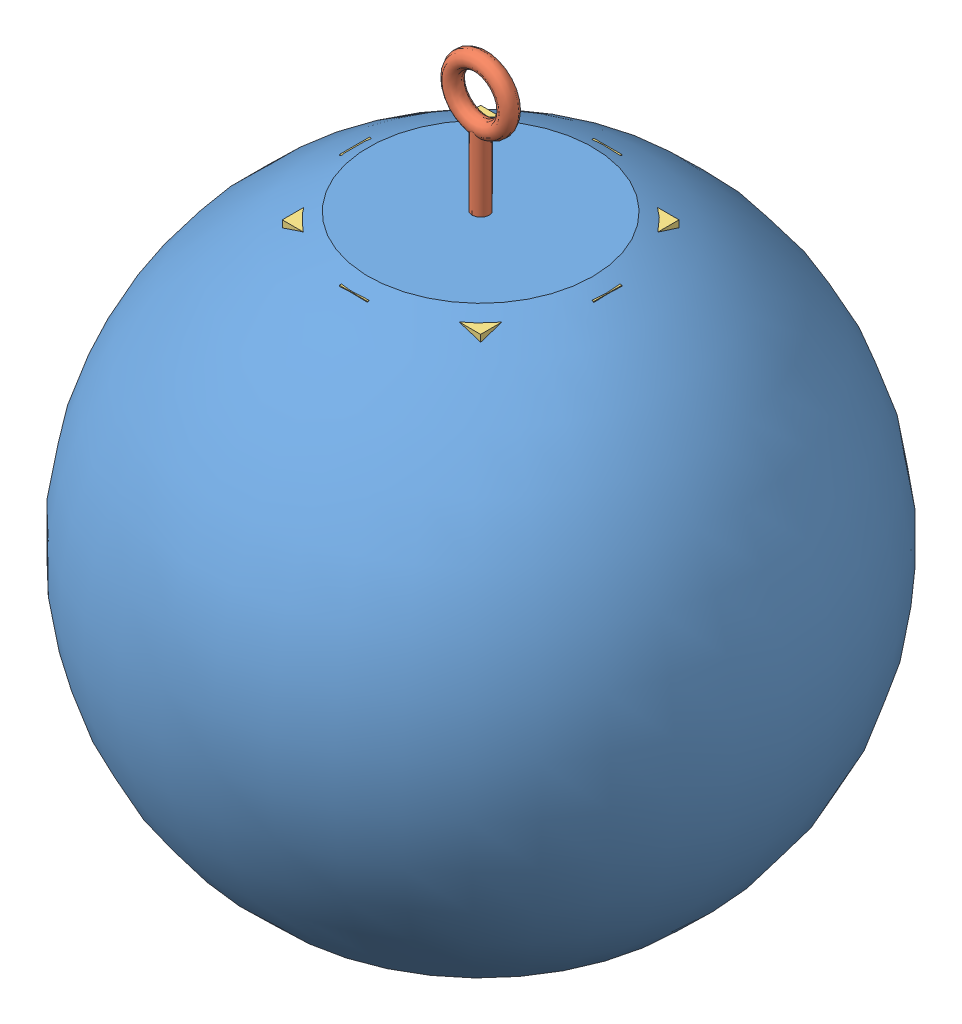
SolidWorks assembly final assembly, configuration Default. Lengths in mm.
Overall size (110 127.03 110).
4 component instances, 3 part files, 3 mates.
Components (placement in the parent):
- orb-1: orb [Default] at origin size (110 102.47 110)
- skeleton_assy-1: skeleton_assy [Default] at (-0.2 37.3 -0.2) size (75 120.8 75)
  - mount-1: mount [Default] at origin size (25 38.5 25)
  - Skeleton_9-1: Skeleton_9 [Default] at (0.2 -37.3 0.2) x (0 0 -1) z (-1 0 0) size (75 95 75)
Mates (geometry in assembly coordinates):
- Coincident1: coincident anti-aligned: plane of skeleton_assy-1/Skeleton_9-1 through (0 0 0) normal (0 -1 0)
- Coincident2: coincident anti-aligned: plane of skeleton_assy-1/Skeleton_9-1 through (0 0 0) normal (0 0 -1)
- Coincident3: coincident anti-aligned: plane of skeleton_assy-1/Skeleton_9-1 through (0 0 0) normal (-1 0 0)
